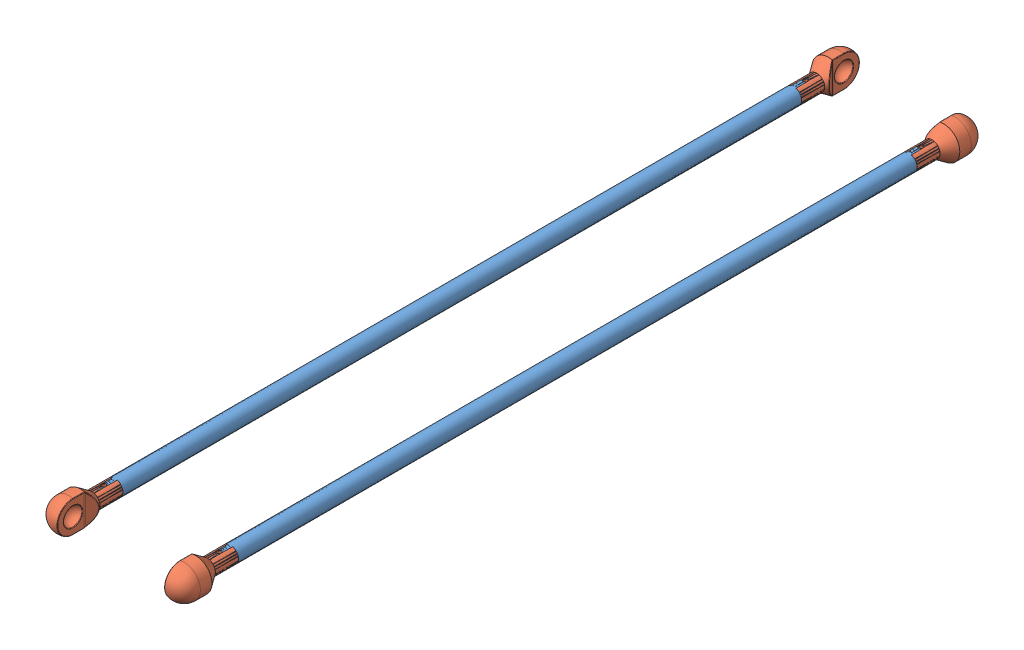
SolidWorks assembly Assemblage4, configuration Défaut. Lengths in mm.
Overall size (64 14 348).
7 component instances, 2 part files, 8 mates.
Components (placement in the parent):
- BarreParalleles2-1: BarreParalleles2 [Défaut] at origin size (57 7 314)
  - Pièce4_Tube-1: Pièce4_Tube [Défaut] at origin size (7 7 314)
  - Pièce4_Tube-2: Pièce4_Tube [Défaut] at (50 0 0) size (7 7 314)
- Pièce4_Extremetees-1: Pièce4_Extremetees [Défaut] at (50 0 -10) x (0 1 0) z (0 0 1) size (14 11.85 27)
- Pièce4_Extremetees-2: Pièce4_Extremetees [Défaut] at (0 0 -10) x (0 -1 0) z (0 0 1) size (14 11.85 27)
- Pièce4_Extremetees-3: Pièce4_Extremetees [Défaut] at (0 0 324) x (0 1 0) z (0 0 -1) size (14 11.85 27)
- Pièce4_Extremetees-4: Pièce4_Extremetees [Défaut] at (50 0 324) x (0 -1 0) z (0 0 -1) size (14 11.85 27)
Mates (geometry in assembly coordinates):
- Coaxiale1: concentric: cylinder of BarreParalleles2-1/Pièce4_Tube-2 through (50 0 314) axis (0 0 -1) radius 3.5; cylinder of Pièce4_Extremetees-1 through (50 0 -17) axis (0 0 -1) radius 3.5
- Coaxiale2: concentric: cylinder of BarreParalleles2-1/Pièce4_Tube-1 through (0 0 314) axis (0 0 -1) radius 3.5; cylinder of Pièce4_Extremetees-2 through (0 0 -17) axis (0 0 -1) radius 3.5
- Coaxiale3: concentric aligned: cylinder of BarreParalleles2-1/Pièce4_Tube-2 through (50 10 5) axis (0 -1 0) radius 1; cylinder of Pièce4_Extremetees-1 through (50 10 5) axis (0 -1 0) radius 1
- Coaxiale4: concentric anti-aligned: cylinder of BarreParalleles2-1/Pièce4_Tube-1 through (0 10 5) axis (0 -1 0) radius 1; cylinder of Pièce4_Extremetees-2 through (0 -10 5) axis (0 1 0) radius 1
- Coaxiale5: concentric: cylinder of BarreParalleles2-1/Pièce4_Tube-1 through (0 0 314) axis (0 0 -1) radius 3.5; cylinder of Pièce4_Extremetees-3 through (0 0 331) axis (0 0 1) radius 3.5
- Coaxiale6: concentric aligned: cylinder of BarreParalleles2-1/Pièce4_Tube-1 through (0 10 309) axis (0 -1 0) radius 1; cylinder of Pièce4_Extremetees-3 through (0 10 309) axis (0 -1 0) radius 1
- Coaxiale7: concentric: cylinder of BarreParalleles2-1/Pièce4_Tube-2 through (50 0 314) axis (0 0 -1) radius 3.5; cylinder of Pièce4_Extremetees-4 through (50 0 331) axis (0 0 1) radius 3.5
- Coaxiale8: concentric anti-aligned: cylinder of BarreParalleles2-1/Pièce4_Tube-2 through (50 10 309) axis (0 -1 0) radius 1; cylinder of Pièce4_Extremetees-4 through (50 -10 309) axis (0 1 0) radius 1
